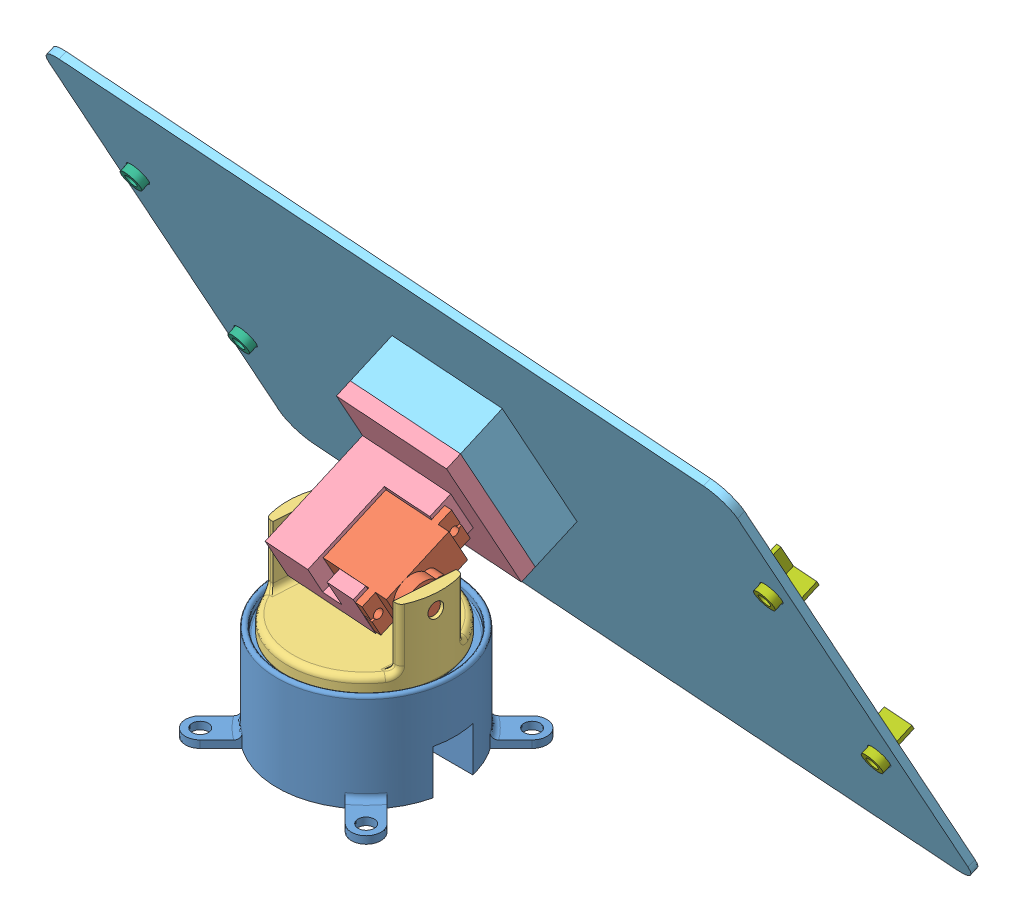
SolidWorks assembly Assembly, configuration Default. Lengths in mm.
Overall size (255.99 158.02 129.59).
10 component instances, 7 part files, 25 mates.
Components (placement in the parent):
- Gimbal Base-2: Gimbal Base [Default] at (-62.8889 -12.2261 19.9576) size (65.98 33 65.98)
- Servo Model-3: Servo Model [Default] at (-67.9072 41.1412 15.7018) x (0.032455 -0.880817 -0.472344) z (-0.060378 -0.473458 0.878745) size (12.5 30.1 32.1)
- Servo Model-4: Servo Model [Default] at (-67.9389 -9.2261 20.4576) x (0 0 -1) z (1 0 0) size (12.5 30.1 32.1)
- Yaw Frame-2: Yaw Frame [Default] at (-62.9389 17.7739 20.4576) x (-0.997648 0 -0.068548) z (0.068548 0 -0.997648) size (52 26 52)
- Pitch Device-2: Pitch Device [Default] at (-83.2862 41.8041 13.4091) x (0.032455 -0.880817 -0.472344) z (0.997648 0 0.068548) size (50 40 43)
- Solar Panel-2: Solar Panel [Default] at (-60.5498 45.4657 -25.7304) x (0.997648 0 0.068548) z (-0.032455 0.880817 0.472344) size (250 17.5 170)
- LDR Holder1-4: LDR Holder1 [Default] at (-176.2967 78.3587 -18.8059) x (0.997648 0 0.068548) z (-0.032455 0.880817 0.472344) size (10 12 10)
- LDR Holder1-5: LDR Holder1 [Default] at (-173.96 14.9399 -52.8147) x (-0.032455 0.880817 0.472344) z (-0.997648 0 -0.068548) size (10 12 10)
- LDR Holder2-3: LDR Holder2 [Default] at (53.1623 78.3587 -3.0398) x (-0.997648 0 -0.068548) z (0.032455 -0.880817 -0.472344) size (10 12 10)
- LDR Holder2-4: LDR Holder2 [Default] at (55.499 14.9399 -37.0486) x (-0.032455 0.880817 0.472344) z (-0.997648 0 -0.068548) size (10 12 10)
Mates (geometry in assembly coordinates):
- Coincident44: coincident anti-aligned: plane of Gimbal Base-2 through (-32.8889 -12.2261 26.7076) normal (0 0 -1); plane of Servo Model-4 through (-79.1889 9.7739 26.7076) normal (0 0 1)
- Coincident46: coincident anti-aligned: plane of Gimbal Base-2 through (-62.8889 7.2739 19.9576) normal (0 1 0); plane of Servo Model-4 through (-67.9389 7.2739 20.4576) normal (0 -1 0)
- Concentric10: concentric aligned: cylinder of Servo Model-4 through (-62.9389 17.8739 20.4576) axis (0 -1 0) radius 6.25; cylinder of Yaw Frame-2 through (-62.9389 23.7739 20.4576) axis (0 -1 0) radius 2.5
- Coincident47: coincident anti-aligned: plane of Gimbal Base-2 through (-62.8889 17.7739 19.9576) normal (0 1 0); plane of Yaw Frame-2 through (-62.9389 17.7739 20.4576) normal (0 -1 0)
- Concentric11: concentric aligned: cylinder of Servo Model-3 through (-41.1728 38.7739 21.9532) axis (-0.997648 0 -0.068548) radius 6.25; cylinder of Yaw Frame-2 through (-37.0001 38.7739 22.2399) axis (-0.997648 0 -0.068548) radius 2.5
- Coincident48: coincident anti-aligned: plane of Servo Model-3 through (-41.0069 40.0754 19.5377) normal (0.997648 0 0.068548); plane of Yaw Frame-2 through (-41.8583 43.7739 31.9297) normal (-0.997648 0 -0.068548)
- Coincident49: coincident anti-aligned: plane of Servo Model-3 through (-67.9072 41.1412 15.7018) normal (-0.997648 0 -0.068548); plane of Pitch Device-2 through (-67.8227 41.8041 14.4716) normal (0.997648 0 0.068548)
- Concentric12: concentric aligned: cylinder of Yaw Frame-2 through (-88.8778 38.7739 18.6754) axis (0.997648 0 0.068548) radius 3.25; cylinder of Pitch Device-2 through (-86.6656 38.7739 18.8274) axis (0.997648 0 0.068548) radius 2.5
- Parallel20: parallel anti-aligned: plane of Servo Model-3 through (-48.4755 51.9727 10.0705) normal (0.060378 0.473458 -0.878745); plane of Pitch Device-2 through (-67.2189 46.5387 5.6841) normal (-0.060378 -0.473458 0.878745)
- Coincident51: coincident anti-aligned: plane of Pitch Device-2 through (-81.9277 52.4569 -6.3627) normal (0.060378 0.473458 -0.878745); plane of Solar Panel-2 through (-61.4555 38.3638 -12.5492) normal (-0.060378 -0.473458 0.878745)
- Coincident52: coincident aligned: plane of Pitch Device-2 through (-82.7391 74.4773 5.4459) normal (-0.032455 0.880817 0.472344); plane of Solar Panel-2 through (-82.7391 74.4773 5.4459) normal (-0.032455 0.880817 0.472344)
- Coincident53: coincident aligned: plane of Pitch Device-2 through (-83.2862 41.8041 13.4091) normal (-0.997648 0 -0.068548); plane of Solar Panel-2 through (-82.7391 74.4773 5.4459) normal (-0.997648 0 -0.068548)
- Concentric13: concentric aligned: cylinder of Solar Panel-2 through (-176.4477 77.1751 -16.6091) axis (0.060378 0.473458 -0.878745) radius 3.75; cylinder of LDR Holder1-4 through (-176.5986 75.9914 -14.4122) axis (0.060378 0.473458 -0.878745) radius 3.5
- Coincident54: coincident anti-aligned: plane of Solar Panel-2 through (-60.3988 46.6493 -27.9273) normal (0.060378 0.473458 -0.878745); plane of LDR Holder1-4 through (-176.2967 78.3587 -18.8059) normal (-0.060378 -0.473458 0.878745)
- Parallel21: parallel aligned: plane of Solar Panel-2 through (-182.3462 -28.2201 -76.645) normal (-0.997648 0 -0.068548); plane of LDR Holder1-4 through (-181.0623 74.4281 -22.3891) normal (-0.997648 0 -0.068548)
- Concentric14: concentric aligned: cylinder of Solar Panel-2 through (-174.1109 13.7563 -50.6178) axis (0.060378 0.473458 -0.878745) radius 3.75; cylinder of LDR Holder1-5 through (-174.2619 12.5726 -48.421) axis (0.060378 0.473458 -0.878745) radius 3.5
- Coincident56: coincident anti-aligned: plane of Solar Panel-2 through (-60.3988 46.6493 -27.9273) normal (0.060378 0.473458 -0.878745); plane of LDR Holder1-5 through (-173.96 14.9399 -52.8147) normal (-0.060378 -0.473458 0.878745)
- Parallel22: parallel aligned: plane of Solar Panel-2 through (-182.3462 -28.2201 -76.645) normal (-0.997648 0 -0.068548); plane of LDR Holder1-5 through (-178.7256 11.0093 -56.3979) normal (-0.997648 0 -0.068548)
- Concentric15: concentric aligned: cylinder of Solar Panel-2 through (53.0113 77.1751 -0.843) axis (0.060378 0.473458 -0.878745) radius 3.75; cylinder of LDR Holder2-3 through (52.8604 75.9914 1.3539) axis (0.060378 0.473458 -0.878745) radius 3.5
- Coincident58: coincident anti-aligned: plane of Solar Panel-2 through (-60.3988 46.6493 -27.9273) normal (0.060378 0.473458 -0.878745); plane of LDR Holder2-3 through (53.1623 78.3587 -3.0398) normal (-0.060378 -0.473458 0.878745)
- Parallel24: parallel aligned: plane of Solar Panel-2 through (67.0658 -28.2201 -59.5079) normal (0.997648 0 0.068548); plane of LDR Holder2-3 through (58.0486 83.2363 -1.2141) normal (0.997648 0 0.068548)
- Concentric16: concentric aligned: cylinder of Solar Panel-2 through (55.3481 13.7563 -34.8517) axis (0.060378 0.473458 -0.878745) radius 3.75; cylinder of LDR Holder2-4 through (55.1971 12.5726 -32.6549) axis (0.060378 0.473458 -0.878745) radius 3.5
- Parallel25: parallel aligned: plane of Solar Panel-2 through (67.0658 -28.2201 -59.5079) normal (0.997648 0 0.068548); plane of LDR Holder2-4 through (60.7099 11.0093 -39.9463) normal (0.997648 0 0.068548)
- Coincident62: coincident anti-aligned: plane of Solar Panel-2 through (-60.3988 46.6493 -27.9273) normal (0.060378 0.473458 -0.878745); plane of LDR Holder2-4 through (55.499 14.9399 -37.0486) normal (-0.060378 -0.473458 0.878745)
- Coincident63: coincident anti-aligned: plane of Gimbal Base-2 through (-51.8889 7.2739 13.2076) normal (-1 0 0); plane of Servo Model-4 through (-51.8889 7.2739 26.7076) normal (1 0 0)
